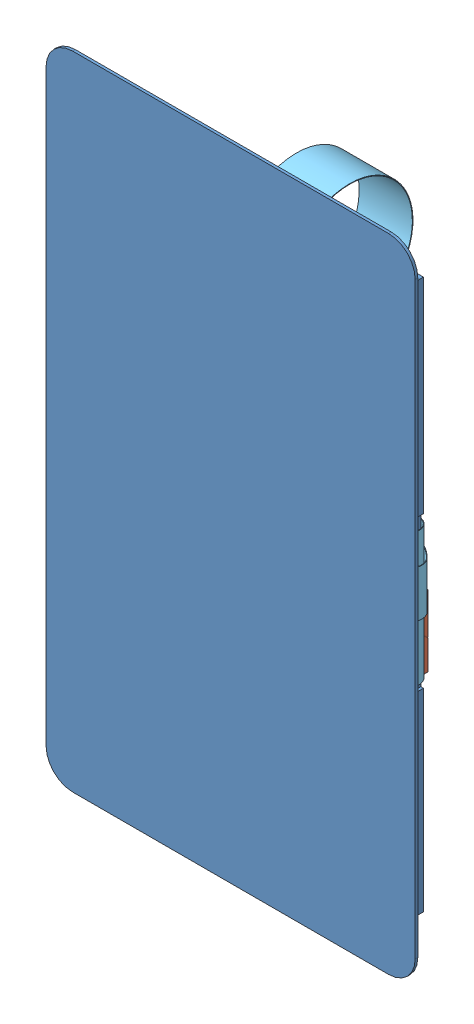
SolidWorks assembly raspberry pi display, configuration Default. Lengths in mm.
Overall size (111 193 50.38).
13 component instances, 6 part files, 0 mates.
Components (placement in the parent):
- raspberry pi display.stp-1: raspberry pi display.stp [Default] at origin size (111 193 50.38)
  - raspberry pi display_1.stp-1: raspberry pi display_1.stp [Default] at (-106.8983 27.1208 1.8078) size (111 193 8.9)
  - Raspberry Pi 3 .stp-1: Raspberry Pi 3 .stp [Default] at (-107.8876 17.1288 -20.0222) x (0 -1 0) z (0 0 -1) size (89.64 57.31 18.59)
  - raspberry pi display module.stp-1: raspberry pi display module.stp [Default] at (-138.2983 -19.3534 -7.6922) x (0 1 0) z (0 0 1) size (67.17 56 8.3)
  - стойка 12мм.stp-1: стойка 12мм.stp [Default] at (-85.7983 62.0708 -19.6922) size (5 5.77 16)
  - стойка 12мм.stp-2: стойка 12мм.stp [Default] at (-134.7983 62.0708 -19.6922) size (5 5.77 16)
  - стойка 12мм.stp-3: стойка 12мм.stp [Default] at (-85.7983 4.0708 -19.6922) size (5 5.77 16)
  - стойка 12мм.stp-4: стойка 12мм.stp [Default] at (-134.7983 4.0708 -19.6922) size (5 5.77 16)
  - cables.stp-1: cables.stp [Default] at (-118.4456 66.2374 -7.6922) x (-1 0 0) z (0 1 0) size (71.97 49.58 93.14)
  - ISO 7045 - M2,5 x 3 - 4.8 - H.stp-1: ISO 7045 - M2,5 x 3 - 4.8 - H.stp [Default] at (-85.7983 62.0708 -21.0222) x (0 0 1) z (0 1 0) size (5.08 5 5)
  - ISO 7045 - M2,5 x 3 - 4.8 - H.stp-2: ISO 7045 - M2,5 x 3 - 4.8 - H.stp [Default] at (-85.7983 4.0708 -21.0222) x (0 0 1) z (0 1 0) size (5.08 5 5)
  - ISO 7045 - M2,5 x 3 - 4.8 - H.stp-3: ISO 7045 - M2,5 x 3 - 4.8 - H.stp [Default] at (-134.7983 4.0708 -21.0222) x (0 0 1) z (0 1 0) size (5.08 5 5)
  - ISO 7045 - M2,5 x 3 - 4.8 - H.stp-4: ISO 7045 - M2,5 x 3 - 4.8 - H.stp [Default] at (-134.7983 62.0708 -21.0222) x (0 0 1) z (0 1 0) size (5.08 5 5)
